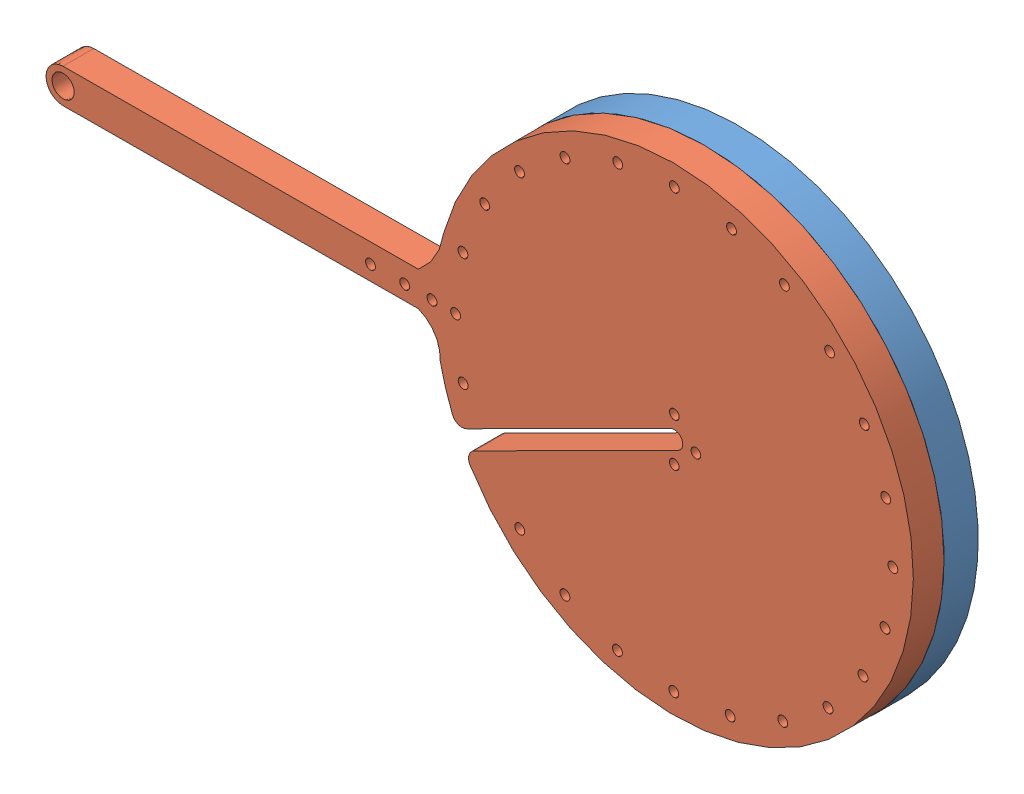
SolidWorks assembly Assem1, configuration Default. Lengths in mm.
Overall size (254.21 140.56 19).
2 component instances, 2 part files, 3 mates.
Components (placement in the parent):
- paddle_arm_extension_smaller_radius-1: paddle_arm_extension_smaller_radius [Default] at (-116.2115 -14.238 31.4227) size (140 140 10)
- Padde_arm_updated_smaller_radius-1: Padde_arm_updated_smaller_radius [Default] at (-116.2484 -14.3911 41.4227) x (0.999998 -0.002189 0) z (0 0 1) size (253.91 140 9)
Mates (geometry in assembly coordinates):
- Coincident1: coincident anti-aligned: plane of paddle_arm_extension_smaller_radius-1 through (-137.677 -13.936 41.4227) normal (0 0 1); plane of Padde_arm_updated_smaller_radius-1 through (-71.5644 1.9737 41.4227) normal (0 0 -1)
- Concentric2: concentric aligned: circle of paddle_arm_extension_smaller_radius-1; circle of Padde_arm_updated_smaller_radius-1
- Concentric3: concentric aligned: circle of paddle_arm_extension_smaller_radius-1; circle of Padde_arm_updated_smaller_radius-1
